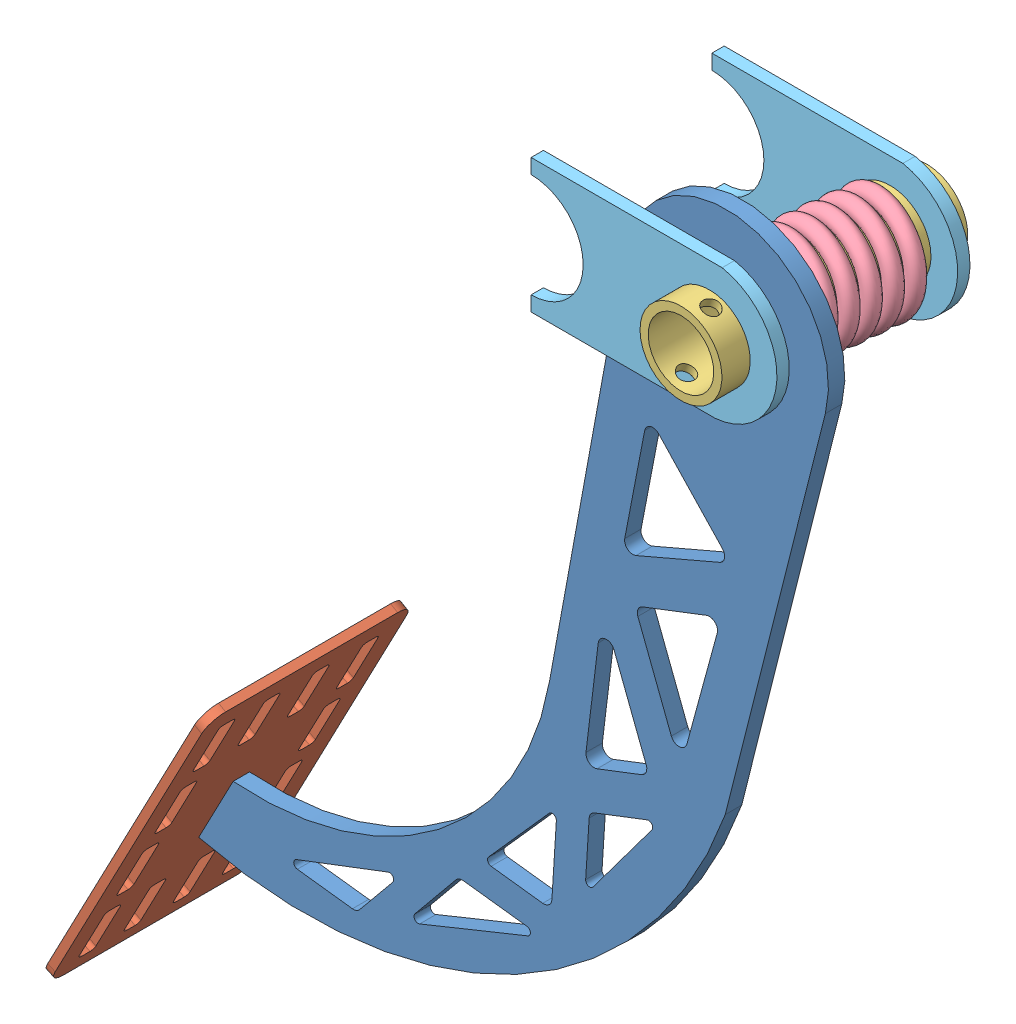
SolidWorks assembly Assem1, configuration Default. Lengths in mm.
Overall size (410.95 410.95 72).
6 component instances, 5 part files, 9 mates.
Components (placement in the parent):
- pedal plate_1-1: pedal plate_1 [Default] at (96.1574 190.1877 176.065) x (0.99273 -0.120364 0) z (0 0 1) size (132.05 212.19 4)
- pedal face-1: pedal face [Default] at (-45.5957 35.7107 153.065) x (0.464218 0.885721 0) z (0.885721 -0.464218 0) size (85.18 50 2)
- rod-1: rod [Default] at (96.1574 190.1877 131.065) x (0.942393 -0.334509 0) z (0 0 1) size (20 20 60)
- torsional_spring-1: torsional_spring [Default] at (98.4936 189.6503 142.8329) x (0.656103 0.753093 0.048786) z (-0.086855 0.011136 0.996159) size (37.07 30 43.03)
- mount-1: mount [Default] at (96.1574 190.1877 137.0569) x (-1 0 0) z (0 0 1) size (59.99 32.68 3)
- mount-2: mount [Default] at (96.1574 190.1877 181.1659) x (-1 0 0) z (0 0 1) size (59.99 32.68 3)
Mates (geometry in assembly coordinates):
- Coincident8: coincident: line of assembly; line of assembly; line of pedal plate_1-1 through (-24.1461 34.0654 180.065) axis (0 0 -1); line of pedal face-1 through (-24.1461 34.0654 180.065) axis (0 0 -1)
- Coincident10: coincident: line of assembly; line of assembly; line of pedal plate_1-1 through (-24.1461 34.0654 180.065) axis (-0.464218 -0.885721 0); line of pedal face-1 through (-24.1461 34.0654 180.065) axis (-0.464218 -0.885721 0)
- Concentric1: concentric: circle of assembly; circle of assembly; circle of pedal plate_1-1; circle of rod-1
- Concentric2: concentric: circle of assembly; circle of assembly; circle of rod-1; circle of mount-1
- Concentric3: concentric: circle of assembly; circle of assembly; circle of rod-1; circle of mount-2
- Parallel3: parallel: plane of ?; plane of assembly through (0 0 0) normal (1 0 0)
- Distance1: distance = 15 mm: plane of assembly; plane of assembly; plane of pedal plate_1-1 through (96.1574 190.1877 176.065) normal (0 0 -1); plane of rod-1 through (96.1574 190.1877 191.065) normal (0 0 1)
- Parallel4: parallel: plane of assembly through (0 0 0) normal (1 0 0); plane of mount-2 through (52.6863 173.7304 184.1659) normal (-1 0 0); plane of assembly
- Parallel5: parallel: plane of assembly through (0 0 0) normal (1 0 0); plane of mount-1 through (52.6863 173.7304 140.0569) normal (-1 0 0); plane of assembly
